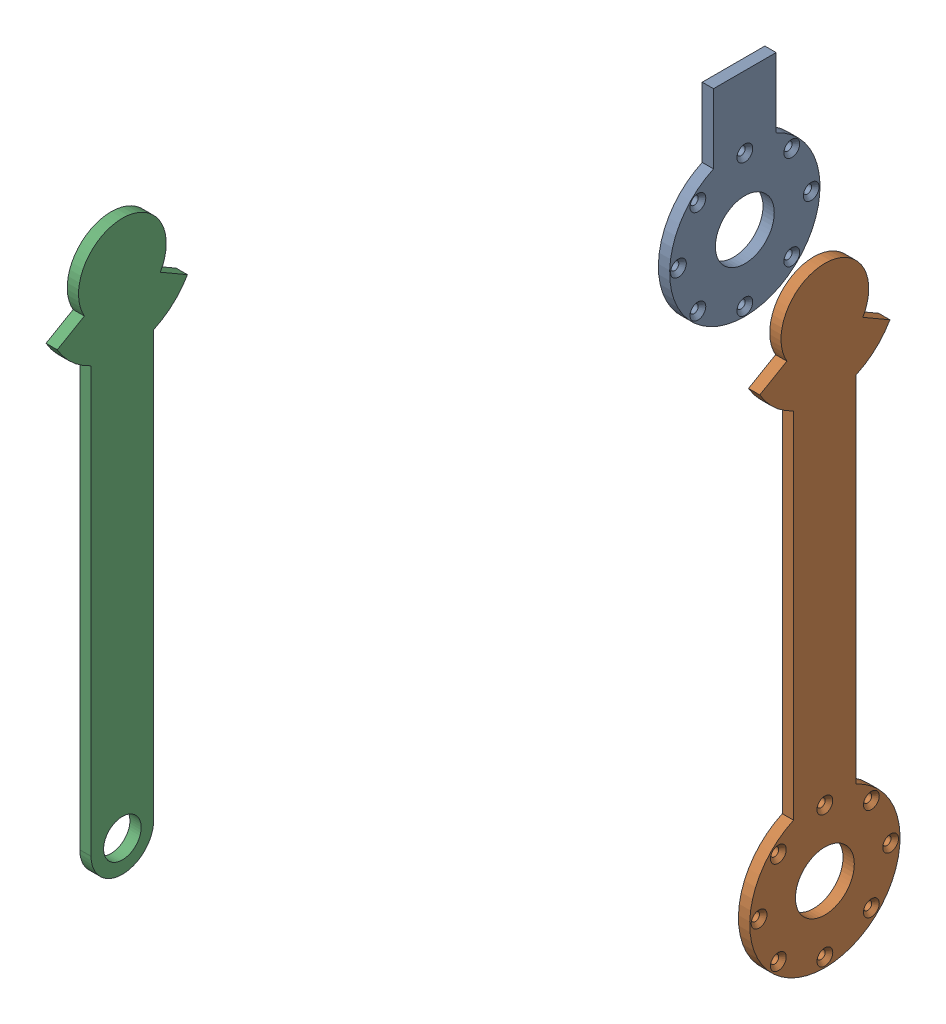
SolidWorks assembly Final Exoskeleton Assembly, configuration Default. Lengths in mm.
Overall size (280.82 549.99 439.19).
3 component instances, 3 part files, 0 mates.
Components (placement in the parent):
- Hip Joint-1: Hip Joint [Default] at (1006.7294 1043.1434 1070.1345) size (9.01 170 120)
- Thigh Link-1: Thigh Link [Default] at (1108.9111 859.1491 1108.4242) size (9 487 120)
- Leg Link-1: Leg Link [Default] at (837.09 898.1065 1397.3631) size (9 453.6 103.92)
